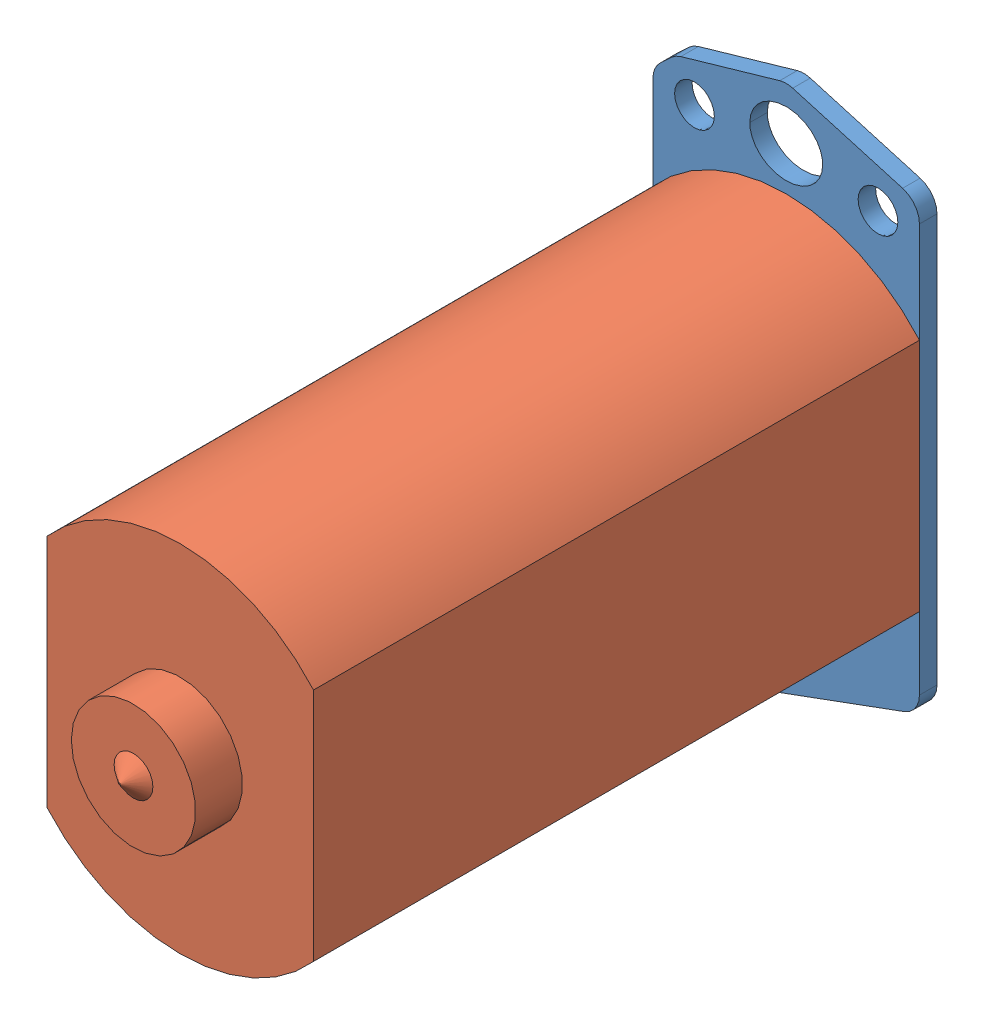
SolidWorks assembly WindowMotor_Motor, configuration Default. Lengths in mm.
Overall size (28.96 59.84 74.35).
2 component instances, 2 part files, 3 mates.
Components (placement in the parent):
- WindowMotor_Motor2-1: WindowMotor_Motor2 [Default] at (44.2087 1.4883 0.2583) size (28.96 59.84 1.91)
- WindowMotor_Motor1-1: WindowMotor_Motor1 [Default] at (44.2087 1.5352 2.1633) size (28.96 38.61 72.44)
Mates (geometry in assembly coordinates):
- Coincident1: coincident aligned: plane of WindowMotor_Motor2-1 through (58.6867 1.3613 -63.6735) normal (1 0 0); plane of WindowMotor_Motor1-1 through (58.6867 -41.0751 -63.6735) normal (1 0 0)
- Coincident2: coincident anti-aligned: plane of WindowMotor_Motor2-1 through (-7.713 1.3613 -63.6735) normal (0 0 1); plane of WindowMotor_Motor1-1 through (44.2087 -41.0751 -63.6735) normal (0 0 -1)
- Distance1: distance = 10.16 mm: point of WindowMotor_Motor2-1; point of WindowMotor_Motor1-1
